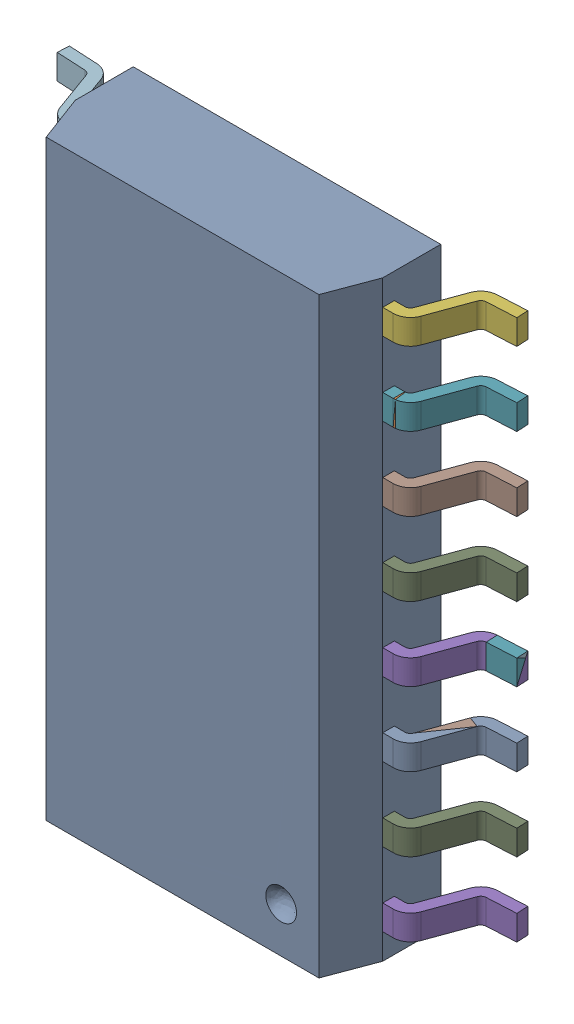
SolidWorks assembly User Library-SOP16_208mil (5.3mm), configuration 默认. Lengths in mm.
Overall size (7.92 10.2 2.07).
29 component instances, 2 part files, 0 mates.
Components (placement in the parent):
- SOP16 Body-1: SOP16 Body [默认] at origin size (5.3 10.2 1.87)
- Foot SOP16-1: Foot SOP16 [默认] at (3.95 -0.85 -0.1979) x (-1 0 0) z (0 0 1) size (1.31 0.43 1.2)
- Foot SOP16-2: Foot SOP16 [默认] at (3.95 -2.12 -0.1979) x (-1 0 0) z (0 0 1) size (1.31 0.43 1.2)
- Foot SOP16-3: Foot SOP16 [默认] at (3.95 -3.39 -0.1979) x (-1 0 0) z (0 0 1) size (1.31 0.43 1.2)
- Foot SOP16-4: Foot SOP16 [默认] at (3.95 -4.66 -0.1979) x (-1 0 0) z (0 0 1) size (1.31 0.43 1.2)
- Foot SOP16-5: Foot SOP16 [默认] at (3.95 0.42 -0.1979) x (-1 0 0) z (0 0 1) size (1.31 0.43 1.2)
- Foot SOP16-6: Foot SOP16 [默认] at (3.95 -0.85 -0.1979) x (-1 0 0) z (0 0 1) size (1.31 0.43 1.2)
- Foot SOP16-7: Foot SOP16 [默认] at (3.95 -2.12 -0.1979) x (-1 0 0) z (0 0 1) size (1.31 0.43 1.2)
- Foot SOP16-8: Foot SOP16 [默认] at (3.95 -3.39 -0.1979) x (-1 0 0) z (0 0 1) size (1.31 0.43 1.2)
- Foot SOP16-9: Foot SOP16 [默认] at (3.95 1.69 -0.1979) x (-1 0 0) z (0 0 1) size (1.31 0.43 1.2)
- Foot SOP16-10: Foot SOP16 [默认] at (3.95 0.42 -0.1979) x (-1 0 0) z (0 0 1) size (1.31 0.43 1.2)
- Foot SOP16-11: Foot SOP16 [默认] at (3.95 -0.85 -0.1979) x (-1 0 0) z (0 0 1) size (1.31 0.43 1.2)
- Foot SOP16-12: Foot SOP16 [默认] at (3.95 -2.12 -0.1979) x (-1 0 0) z (0 0 1) size (1.31 0.43 1.2)
- Foot SOP16-13: Foot SOP16 [默认] at (3.95 2.96 -0.1979) x (-1 0 0) z (0 0 1) size (1.31 0.43 1.2)
- Foot SOP16-14: Foot SOP16 [默认] at (3.95 1.69 -0.1979) x (-1 0 0) z (0 0 1) size (1.31 0.43 1.2)
- Foot SOP16-15: Foot SOP16 [默认] at (3.95 0.42 -0.1979) x (-1 0 0) z (0 0 1) size (1.31 0.43 1.2)
- Foot SOP16-16: Foot SOP16 [默认] at (3.95 -0.85 -0.1979) x (-1 0 0) z (0 0 1) size (1.31 0.43 1.2)
- Foot SOP16-17: Foot SOP16 [默认] at (3.95 4.23 -0.1979) x (-1 0 0) z (0 0 1) size (1.31 0.43 1.2)
- Foot SOP16-18: Foot SOP16 [默认] at (3.95 2.96 -0.1979) x (-1 0 0) z (0 0 1) size (1.31 0.43 1.2)
- Foot SOP16-19: Foot SOP16 [默认] at (3.95 1.69 -0.1979) x (-1 0 0) z (0 0 1) size (1.31 0.43 1.2)
- Foot SOP16-20: Foot SOP16 [默认] at (3.95 0.42 -0.1979) x (-1 0 0) z (0 0 1) size (1.31 0.43 1.2)
- Foot SOP16-21: Foot SOP16 [默认] at (-3.95 2.12 -0.1979) size (1.31 0.43 1.2)
- Foot SOP16-22: Foot SOP16 [默认] at (-3.95 3.39 -0.1979) size (1.31 0.43 1.2)
- Foot SOP16-23: Foot SOP16 [默认] at (-3.95 4.66 -0.1979) size (1.31 0.43 1.2)
- Foot SOP16-24: Foot SOP16 [默认] at (-3.95 0.85 -0.1979) size (1.31 0.43 1.2)
- Foot SOP16-25: Foot SOP16 [默认] at (-3.95 -2.96 -0.1979) size (1.31 0.43 1.2)
- Foot SOP16-26: Foot SOP16 [默认] at (-3.95 -4.23 -0.1979) size (1.31 0.43 1.2)
- Foot SOP16-27: Foot SOP16 [默认] at (-3.95 -1.69 -0.1979) size (1.31 0.43 1.2)
- Foot SOP16-28: Foot SOP16 [默认] at (-3.95 -0.42 -0.1979) size (1.31 0.43 1.2)
